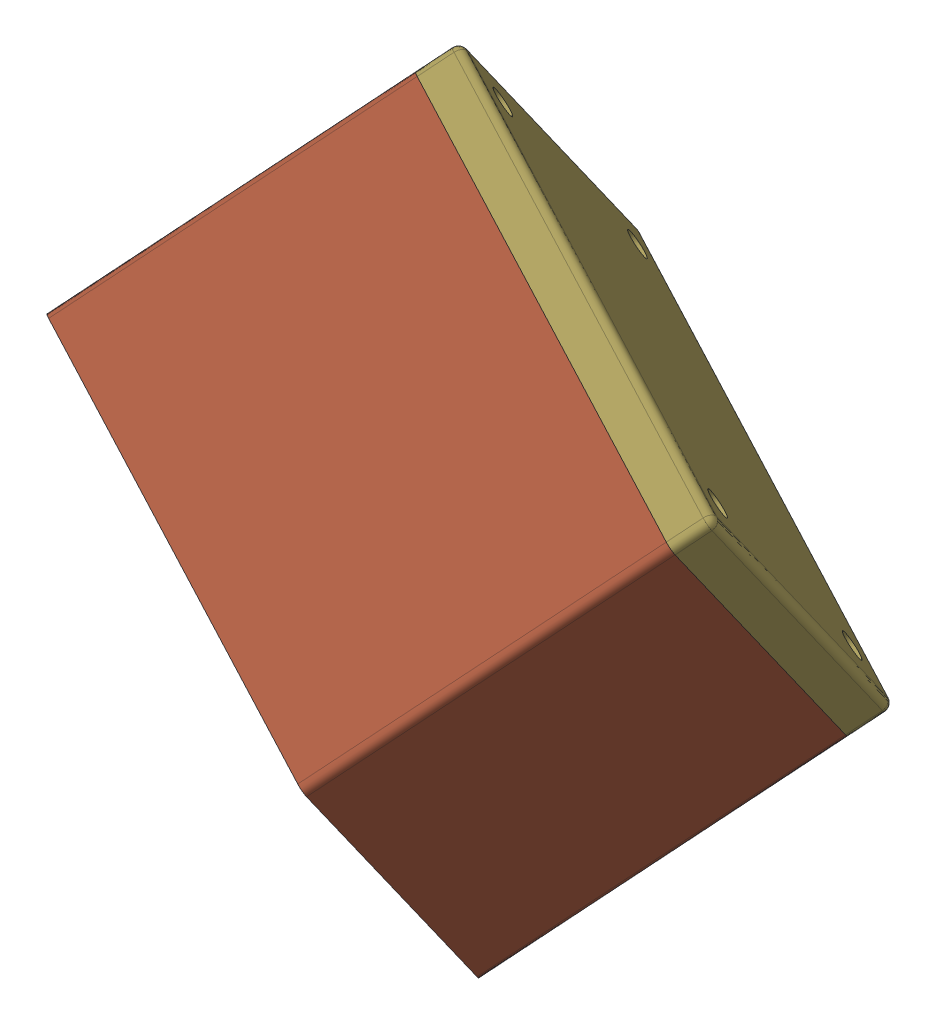
SolidWorks assembly Assem1, configuration Default. Lengths in mm.
Overall size (73.96 71.46 77.39).
34 component instances, 12 part files, 6 mates.
Components (placement in the parent):
- PCB.step-1: PCB.step [Default] at (-148.5299 -12.2625 -75.2397) x (0.89922 -0.259088 0.352529) z (0.437425 0.517776 -0.735233) size (40 23 12.5)
  - C_0805_2012Metric.step-1: C_0805_2012Metric.step [Default] at (164.825 -129.4375 1.65) x (0 -1 0) z (0 0 1) size (2 1.25 1.25)
    - SOLID.step-1: SOLID.step [Default] at origin size (2 1.25 1.25)
  - IDC-Header_2x03_P2.54mm_Vertical.step-1: IDC-Header_2x03_P2.54mm_Vertical.step [Default] at (142 -130.8 1.65) size (9.1 15.28 12.1)
    - SOLID-0.step-1: SOLID-0.step [Default] at origin size (9.1 15.28 12.1)
  - B05B-XASK-1_LF__SN_.step-1: B05B-XASK-1_LF__SN_.step [Default] at (172.6 -123.2 1.65) size (15 6.4 12.2)
    - COMPOUND.step-1: COMPOUND.step [Default] at origin size (15 6.4 12.2)
  - B03B-XASK-1_LF__SN_.step-1: B03B-XASK-1_LF__SN_.step [Default] at (156.6 -123.2 1.65) size (10 6.4 12.2)
    - COMPOUND-1.step-1: COMPOUND-1.step [Default] at origin size (10 6.4 12.2)
  - DIP-4_W8.89mm_SMDSocket.step-1: DIP-4_W8.89mm_SMDSocket.step [Default] at (169.07 -132.65 1.65) x (0 1 0) z (0 0 1) size (10.22 5.2 3.68)
    - SOLID-2.step-1: SOLID-2.step [Default] at origin size (10.22 5.2 3.68)
  - SOIJ-8_5.3x5.3mm_P1.27mm.step-1: SOIJ-8_5.3x5.3mm_P1.27mm.step [Default] at (158.95 -130.035 1.65) size (7.94 5.3 2.01)
    - SOLID-3.step-1: SOLID-3.step [Default] at origin size (7.94 5.3 2.01)
  - SW_SPST_PTS645.step-1: SW_SPST_PTS645.step [Default] at (158.9 -136.9 1.65) x (-1 0 0) z (0 0 1) size (9 6 4.3)
    - SOLID-4.step-1: SOLID-4.step [Default] at origin size (9 6 4.3)
  - R_0805_2012Metric.step-1: R_0805_2012Metric.step [Default] at (173.3 -129.1 1.65) x (0 -1 0) z (0 0 1) size (2 1.2 0.45)
    - SOLID-5.step-1: SOLID-5.step [Default] at origin size (2 1.2 0.45)
  - R_0805_2012Metric.step-2: R_0805_2012Metric.step [Default] at (150.5 -136.8 1.65) size (2 1.2 0.45)
    - SOLID-5.step-1: SOLID-5.step [Default] at origin size (2 1.2 0.45)
  - R_0805_2012Metric.step-3: R_0805_2012Metric.step [Default] at (150.5 -134.6 1.65) size (2 1.2 0.45)
    - SOLID-5.step-1: SOLID-5.step [Default] at origin size (2 1.2 0.45)
  - R_0805_2012Metric.step-4: R_0805_2012Metric.step [Default] at (169.6 -139.7 1.65) size (2 1.2 0.45)
    - SOLID-5.step-1: SOLID-5.step [Default] at origin size (2 1.2 0.45)
  - R_0805_2012Metric.step-5: R_0805_2012Metric.step [Default] at (164.8 -133.25 1.65) x (0 1 0) z (0 0 1) size (2 1.2 0.45)
    - SOLID-5.step-1: SOLID-5.step [Default] at origin size (2 1.2 0.45)
  - R_0805_2012Metric.step-6: R_0805_2012Metric.step [Default] at (150.5 -128.3 1.65) x (-1 0 0) z (0 0 1) size (2 1.2 0.45)
    - SOLID-5.step-1: SOLID-5.step [Default] at origin size (2 1.2 0.45)
  - LED_0805_2012Metric.step-1: LED_0805_2012Metric.step [Default] at (150.475 -132.5 1.65) size (2 1.25 1.1)
    - SOLID-6.step-1: SOLID-6.step [Default] at origin size (2 1.25 1.1)
  - LED_0805_2012Metric.step-2: LED_0805_2012Metric.step [Default] at (150.475 -130.4 1.65) size (2 1.25 1.1)
    - SOLID-6.step-1: SOLID-6.step [Default] at origin size (2 1.25 1.1)
  - COMPOUND-7.step-1: COMPOUND-7.step [Default] at origin size (40 23 1.6)
- bottom-1: bottom [Default] at (-34.5758 39.684 49.5412) x (0.89922 -0.259088 0.352529) z (0.007959 0.815341 0.578926) size (60 40 40)
- top-1: top [Default] at (5.5211 66.148 37.629) x (0.89922 -0.259088 0.352529) z (0.007959 0.815341 0.578926) size (60 5 40)
Mates (geometry in assembly coordinates):
- Coincident1: coincident anti-aligned: plane of PCB.step-1/COMPOUND-7.step-1 through (-5.4145 53.2036 56.0098) normal (-0.437425 -0.517776 0.735233); plane of bottom-1 through (9.76 55.7813 66.8531) normal (0.437425 0.517776 -0.735233)
- Width1: width anti-aligned: plane of bottom-1 through (27.8822 47.4407 37.7583) normal (-0.89922 0.259088 -0.352529); plane of bottom-1 through (-17.0788 60.3951 20.1318) normal (0.89922 -0.259088 0.352529); plane of PCB.step-1/COMPOUND-7.step-1 through (12.6614 57.3982 69.718) normal (0.89922 -0.259088 0.352529); plane of PCB.step-1/COMPOUND-7.step-1 through (-23.4904 49.0089 42.3015) normal (-0.89922 0.259088 -0.352529)
- Width2: width anti-aligned: plane of bottom-1 through (-16.84 84.8553 37.4996) normal (-0.007959 -0.815341 -0.578926); plane of bottom-1 through (-17.0788 60.3951 20.1318) normal (0.007959 0.815341 0.578926); plane of PCB.step-1/COMPOUND-7.step-1 through (-23.3074 67.7618 55.6168) normal (0.007959 0.815341 0.578926); plane of PCB.step-1/COMPOUND-7.step-1 through (12.4784 38.6454 56.4027) normal (-0.007959 -0.815341 -0.578926)
- Coincident2: coincident anti-aligned: plane of bottom-1 through (-17.0788 60.3951 20.1318) normal (0.437425 0.517776 -0.735233); plane of top-1 through (5.5211 66.148 37.629) normal (-0.437425 -0.517776 0.735233)
- Coincident3: coincident aligned: plane of bottom-1 through (-21.6147 57.6138 15.4746) normal (-0.007959 -0.815341 -0.578926); plane of top-1 through (-19.4275 60.2027 11.7984) normal (-0.007959 -0.815341 -0.578926)
- Coincident4: coincident aligned: plane of bottom-1 through (32.3385 42.0685 36.6263) normal (0.89922 -0.259088 0.352529); plane of top-1 through (34.5256 44.6574 32.9501) normal (0.89922 -0.259088 0.352529)
